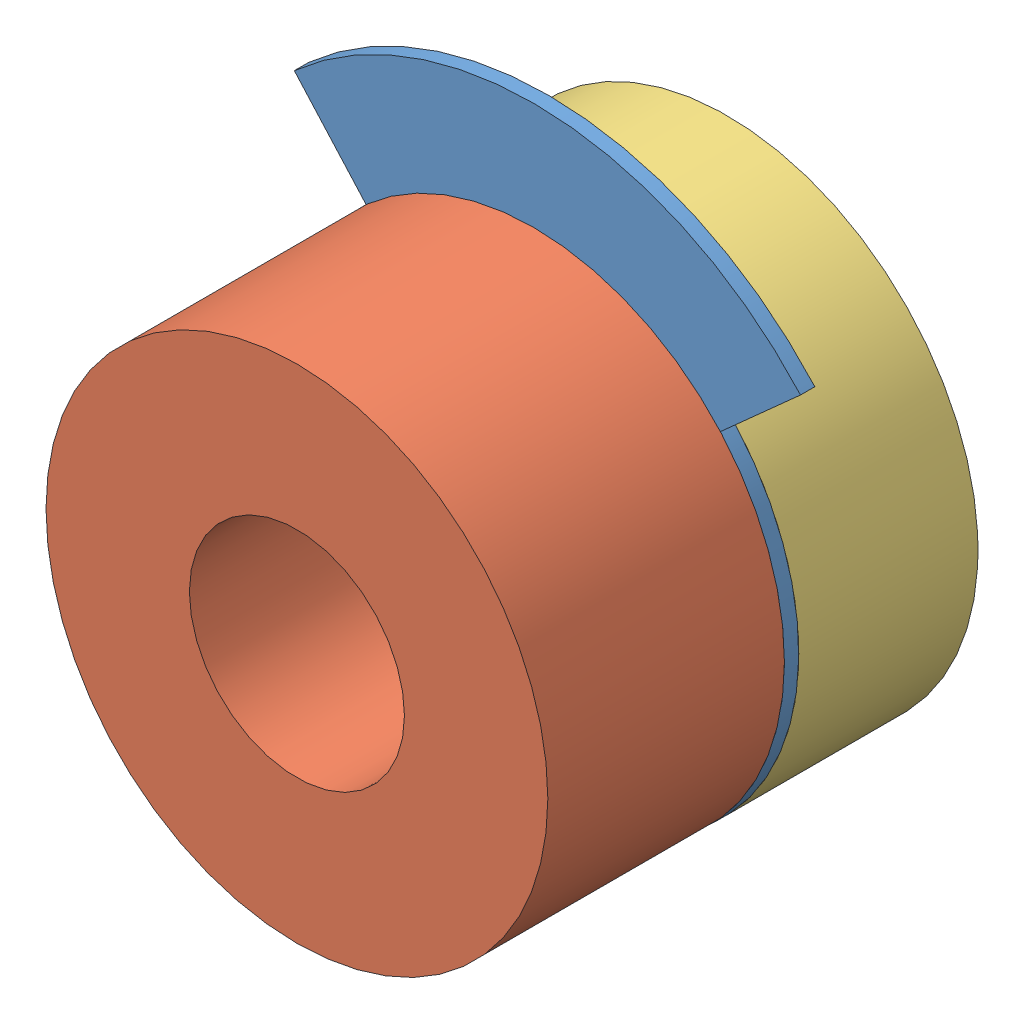
SolidWorks assembly Assemblage1, configuration Défaut. Lengths in mm.
Overall size (36.12 42.5 30).
3 component instances, 3 part files, 4 mates.
Components (placement in the parent):
- disque cible-1: disque cible [Défaut] at origin size (36.12 42.5 1)
- bague coté moteur-2: bague coté moteur [Défaut] at (0 0 1) size (35 35 16.5)
- bague côté extérieur-2: bague côté extérieur [Défaut] at (0 0 -12.5) size (35 35 12.5)
Mates (geometry in assembly coordinates):
- Coaxiale1: concentric aligned: cylinder of disque cible-1 through (0 0 1) axis (0 0 -1) radius 7.5; cylinder of bague coté moteur-2 through (0 0 17.5) axis (0 0 -1) radius 7.5
- Coïncidente1: coincident anti-aligned: plane of disque cible-1 through (0 0 1) normal (0 0 1); plane of bague coté moteur-2 through (0 0 1) normal (0 0 -1)
- Coaxiale2: concentric aligned: cylinder of bague coté moteur-2 through (0 0 17.5) axis (0 0 -1) radius 7.5; cylinder of bague côté extérieur-2 through (0 0 -15.3099) axis (0 0 -1) radius 7.5
- Coïncidente2: coincident anti-aligned: plane of disque cible-1 through (0 0 0) normal (0 0 -1); plane of bague côté extérieur-2 through (0 0 0) normal (0 0 1)
